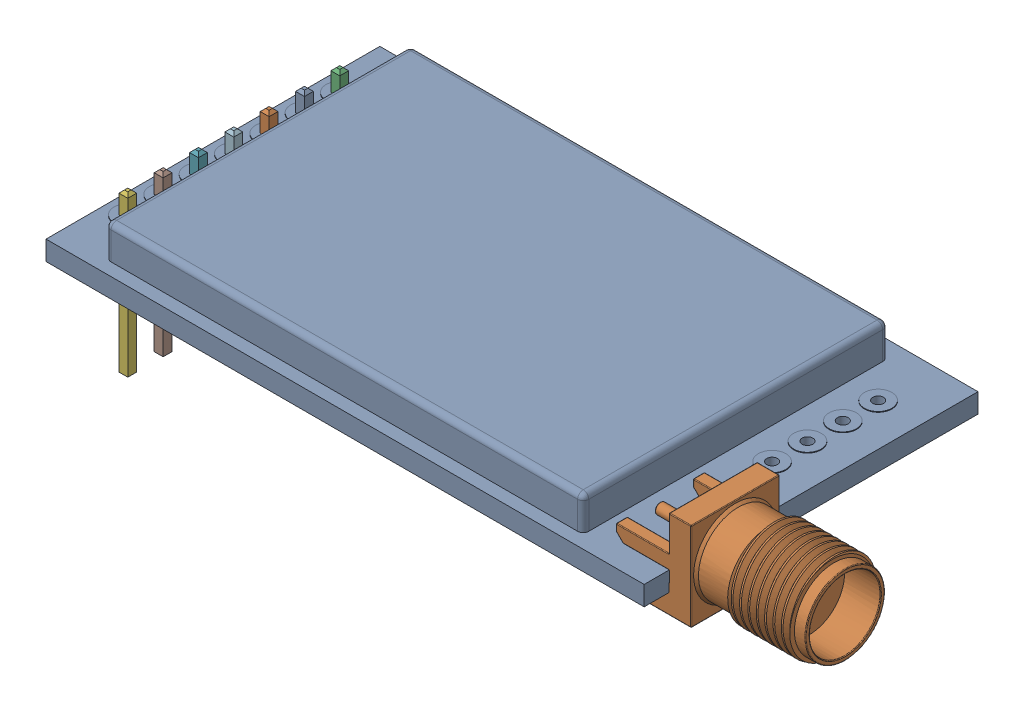
SolidWorks assembly E32-TTL, configuration Default. Lengths in mm.
Overall size (52.5 13.62 24).
5 component instances, 4 part files, 0 mates.
Components (placement in the parent):
- E32-TTL-1W_Predeterminado-1: E32-TTL-1W_Predeterminado [Default] at (-66.873 -19.9517 0) size (43 3.79 24)
- SMA_CONNECTOR_-_EMPCB.SMAFSTJ.B.HT-1: SMA_CONNECTOR_-_EMPCB.SMAFSTJ.B.HT [Default] at (-43.773 -15.0017 10.2201) x (0 0 1) z (1 0 0) size (6.58 6.47 13.3)
- 05__HEADER-3WAY-1ROW-2.54MM-VERTICAL-PCB_Predeterminado-1: 05__HEADER-3WAY-1ROW-2.54MM-VERTICAL-PCB_Predeterminado [Default] at (-87.6961 -24.2405 2.52) x (0 -1 0) z (0 0 1) size (11.55 2.54 7.62)
- 05__HEADER-3WAY-1ROW-2.54MM-VERTICAL-PCB_Predeterminado-2: 05__HEADER-3WAY-1ROW-2.54MM-VERTICAL-PCB_Predeterminado [Default] at (-87.6961 -24.2405 -5.1) x (0 -1 0) z (0 0 1) size (11.55 2.54 7.62)
- HEADER-1WAY-1ROW-2.54MM-VERTICAL-PCB_Predeterminado-1: HEADER-1WAY-1ROW-2.54MM-VERTICAL-PCB_Predeterminado [Default] at (-86.893 -19.9517 -7.64) x (0 -1 0) z (-1 0 0) size (11.54 2.54 2.54)
